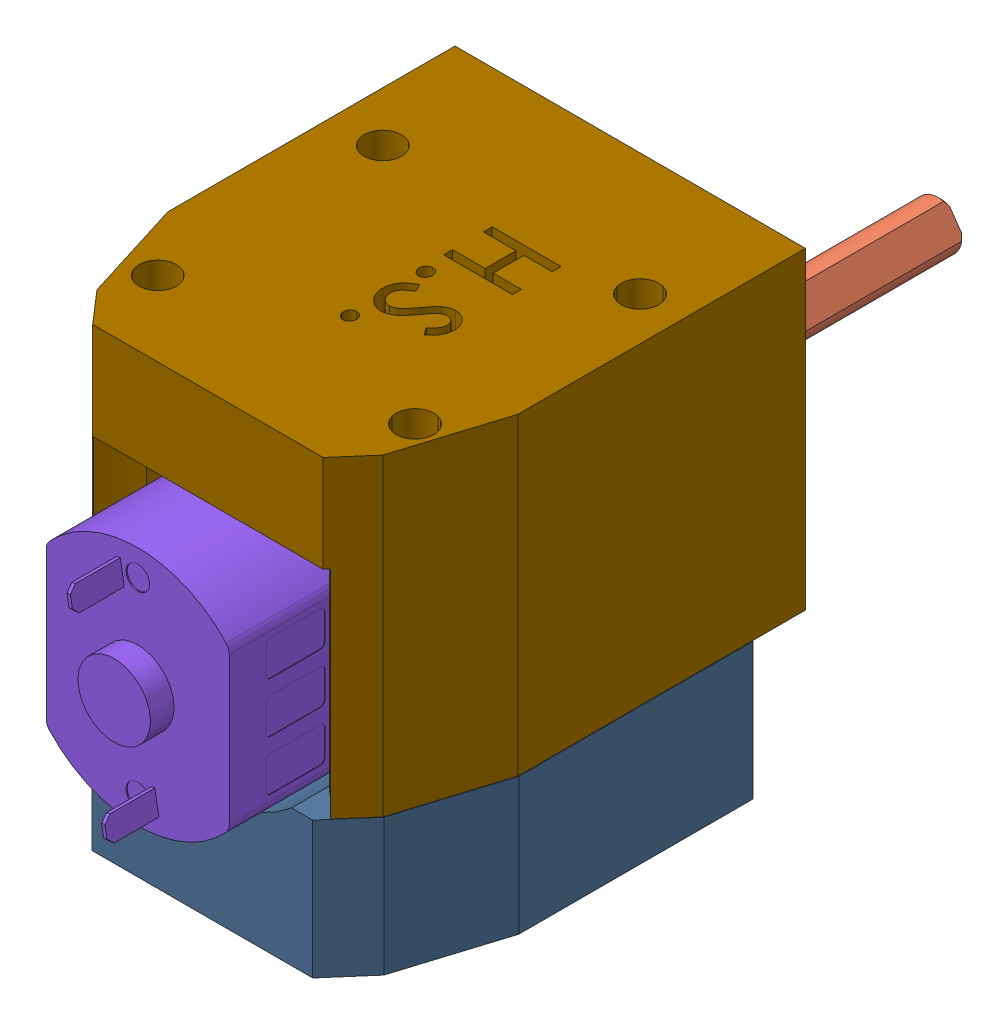
SolidWorks assembly drive mount assembled, configuration Default. Lengths in mm.
Overall size (29.72 38.1 72.3).
19 component instances, 10 part files, 9 mates.
Components (placement in the parent):
- DartBox V2 4mm Shaft-1: DartBox V2 4mm Shaft [Default] at (15.0363 35.1441 34.9065) x (1 0 0) z (0 0 -1) size (21.95 21.95 72.3)
  - DartBox V2 4mm Shaft.stp-1: DartBox V2 4mm Shaft.stp [Default] at origin size (21.95 21.95 72.3)
    - DartBox V2 Drive Gearbox.stp-1: DartBox V2 Drive Gearbox.stp [Default] at (0.1107 15.4459 54.2565) x (0 1 0) z (0 0 1) size (21.95 21.95 42.9)
      - Ring Gear.stp-1: Ring Gear.stp [Default] at (-10.1305 0.1259 -54.0061) x (0 -1 0) z (0 0 1) size (21.95 21.95 40.4)
        - Front Plate.stp-1: Front Plate.stp [Default] at (0.1259 10.1305 56.5061) x (0 1 0) z (1 0 0) size (21.95 30.5 21.95)
          - Shaft.stp-1: Shaft.stp [Default] x (-0.819152 0 -0.573576) z (0.573576 0 -0.819152) size (6.9 30.3 5.94)
            - 98543A103_Side-Mount External Retaining Rings.stp-1: 98543A103_Side-Mount External Retaining Rings.stp [Default] at (0 16.7 0) x (0 1 0) z (0 0 1) size (0.6 6.9 5.94)
            - Shaft-0.stp-1: Shaft-0.stp [Default] at origin size (4 30.3 4)
          - Front Plate-1.stp-1: Front Plate-1.stp [Default] at origin size (21.95 6.5 21.95)
          - Front Plate-2.stp-1: Front Plate-2.stp [Default] at origin size (9.5 6 9.5)
        - Ring Gear Body.stp-1: Ring Gear Body.stp [Default] at (0.1259 10.1305 56.5061) x (0 1 0) z (1 0 0) size (16.5 10.4 16.5)
      - Motor Mount Plate.stp-1: Motor Mount Plate.stp [Default] at (0 0 2.5) x (1 0 0) z (0 -1 0) size (21.95 3.5 21.95)
      - Screws M2 x 14mm.stp-1: Screws M2 x 14mm.stp [Default] at (6.364 6.364 0.9) size (3.4 3.4 15.61)
      - Screws M2 x 14mm.stp-2: Screws M2 x 14mm.stp [Default] at (-6.364 6.364 0.9) x (0 1 0) z (0 0 1) size (3.4 3.4 15.61)
      - Screws M2 x 14mm.stp-3: Screws M2 x 14mm.stp [Default] at (-6.364 -6.364 0.9) x (-1 0 0) z (0 0 1) size (3.4 3.4 15.61)
      - Screws M2 x 14mm.stp-4: Screws M2 x 14mm.stp [Default] at (6.364 -6.364 0.9) x (0 -1 0) z (0 0 1) size (3.4 3.4 15.61)
    - DartBox 130 motor.stp-1: DartBox 130 motor.stp [Default] at (0.1107 15.4459 54.2565) x (1 0 0) z (0 0 -1) size (15.5 20.4 34.9)
- Shock Mount bottom-1: Shock Mount bottom [Default] at (15.15 35.1146 35.012) x (1 0 0) z (0 0 -1) size (29.66 26.52 35.75)
- Shock Mount Top-1: Shock Mount Top [Default] at (15.494 35.1146 35.512) x (1 0 0) z (0 0 -1) size (29.72 11.58 31.75)
Mates (geometry in assembly coordinates):
- Coincident1: coincident anti-aligned: plane of DartBox V2 4mm Shaft-1/DartBox V2 4mm Shaft.stp-1/DartBox 130 motor.stp-1 through (22.897 19.6982 5.75) normal (1 0 0); plane of Shock Mount bottom-1 through (22.897 29.909 -0.5) normal (-1 0 0)
- Coincident2: coincident anti-aligned: plane of DartBox V2 4mm Shaft-1/DartBox V2 4mm Shaft.stp-1/DartBox V2 Drive Gearbox.stp-1/Ring Gear.stp-1/Ring Gear Body.stp-1 through (22.385 27.9482 -19.35) normal (0 1 0); plane of Shock Mount bottom-1 through (6.9 27.9482 -32.25) normal (0 -1 0)
- Coincident3: coincident anti-aligned: plane of DartBox V2 4mm Shaft-1/DartBox V2 4mm Shaft.stp-1/DartBox V2 Drive Gearbox.stp-1/Ring Gear.stp-1/Front Plate.stp-1/Front Plate-1.stp-1 through (15.147 19.6982 -32.25) normal (0 0 1); plane of Shock Mount bottom-1 through (15.15 19.6982 -32.25) normal (0 0 -1)
- Coincident4: coincident anti-aligned: plane of Shock Mount bottom-1 through (23.4 11.5752 -32.25) normal (0 -1 0); plane of Shock Mount Top-1 through (14.859 11.5752 -15.875) normal (0 1 0)
- Coincident5: coincident aligned: plane of Shock Mount bottom-1 through (26.15 11.5752 -21.9884) normal (0 0 1); plane of Shock Mount Top-1 through (15.994 19.6982 -21.9884) normal (0 0 1)
- Coincident6: coincident aligned: plane of Shock Mount bottom-1 through (0 33.4142 -0.5) normal (-1 0 0); plane of Shock Mount Top-1 through (0 3.8838 -31.75) normal (-1 0 0)
- Coincident7: coincident anti-aligned: plane of Shock Mount Top-1 through (0 3.8838 -31.75) normal (-1 0 0)
- Coincident8: coincident aligned: plane of Shock Mount Top-1 through (33.274 11.5752 0) normal (0 0 1)
- Coincident9: coincident anti-aligned: plane of Shock Mount Top-1 through (12.8539 0 20.9) normal (0 -1 0)
